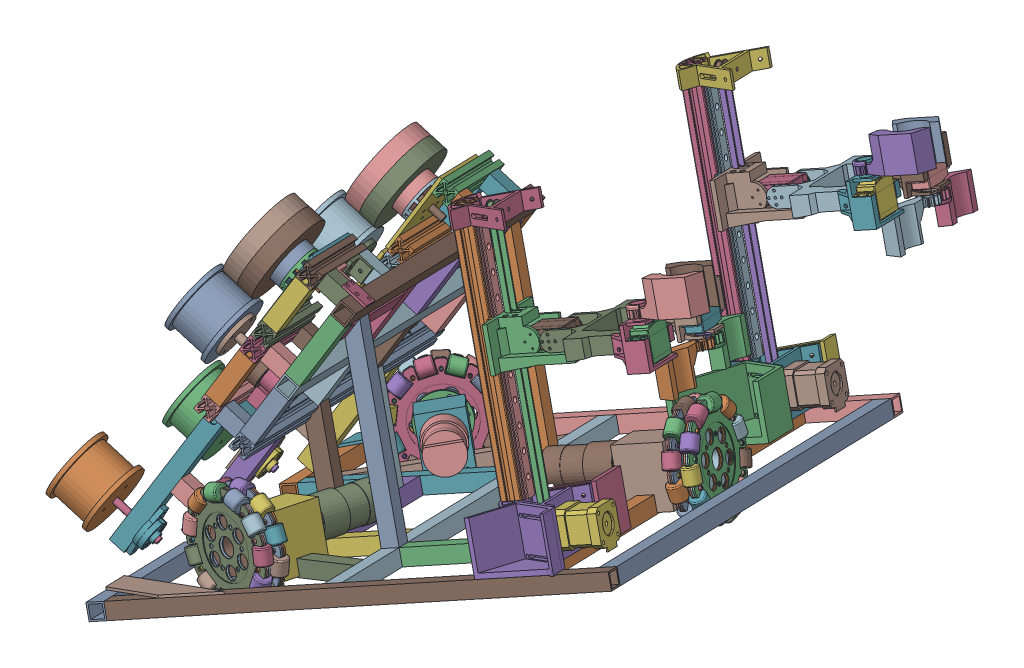
SolidWorks assembly R1 Matlab Sim, configuration Default. Lengths in mm.
Overall size (955.95 722.96 972.76).
16 component instances, 6 part files, 35 mates.
Components (placement in the parent):
- R1 Chassis 6.0^r1 new chassis final part-1: R1 Chassis 6.0^r1 new chassis final part [Default] at (-4184.0722 -937.4255 -3816.6407) x (0.301607 0.282787 0.91053) z (-0.870861 -0.307048 0.383828) size (641.16 369 671.98)
- Omni wheel 127 part-1: Omni wheel 127 part [Default] at (-4602.7717 -1004.8804 -2863.0443) x (0.986722 -0.097143 0.130163) z (-0.118658 0.116072 0.986128) size (127.02 126 38)
- Omni wheel 127 part-2: Omni wheel 127 part [Default] at (-4339.3403 -953.648 -3225.4474) x (0.274362 -0.951568 -0.138723) z (-0.870861 -0.307048 0.383828) size (127.02 126 38)
- Omni wheel 127 part-3: Omni wheel 127 part [Default] at (-4745.1531 -1138.3774 -3292.8838) x (0.680114 -0.674599 -0.286985) z (-0.658494 -0.39008 -0.643601) size (127.02 126 38)
- Flipping_with_dual_shaft part-1: Flipping_with_dual_shaft part [Default] at (-4513.2105 -869.8457 -3469.0567) x (-0.301607 -0.282787 -0.91053) z (0.870861 0.307048 -0.383828) size (100 50 97.1)
- Flipping_with_dual_shaft part-2: Flipping_with_dual_shaft part [Default] at (-4360.7057 -732.4356 -3013.1182) x (-0.301607 -0.282787 -0.91053) z (0.870861 0.307048 -0.383828) size (100 50 97.1)
- Flipping_with_dual_shaft gripper part-1: Flipping_with_dual_shaft gripper part [Default] at (-4514.6412 -878.2751 -3444.5959) x (-0.313424 -0.286937 -0.905225) z (0.907949 0.188715 -0.374185) size (170.89 81.02 142.51)
- Flipping_with_dual_shaft gripper part-2: Flipping_with_dual_shaft gripper part [Default] at (-4362.8301 -741.5154 -2990.7516) x (-0.313424 -0.286937 -0.905225) z (0.907949 0.188715 -0.374185) size (170.89 81.02 142.51)
- gripper v4 gear-1: gripper v4 gear [Metric - Spur gear 1.5M 14T 20PA 10FW ---S14N75H50L3N] at (-4212.9658 -623.4447 -3023.6832) x (-0.388118 0.90871 -0.15366) z (-0.301607 -0.282787 -0.91053) size (40 86 32)
- spur_gear-1: spur_gear [Default] at (-4221.1679 -625.0695 -3042.6017) x (0.388118 -0.90871 0.15366) z (0.48783 0.344021 0.802291) size (40 83.91 29.51)
- spur_gear-2: spur_gear [Default] at (-4375.8917 -844.939 -3571.7047) x (-0.388118 0.90871 -0.15366) z (0.91614 0.362275 -0.171592) size (40 83.91 29.51)
- spur_gear-3: spur_gear [Default] at (-4372.979 -761.8292 -3496.446) x (0.388118 -0.90871 0.15366) z (0.48783 0.344021 0.802291) size (40 83.91 29.51)
- spur_gear-4: spur_gear [Default] at (-4224.0806 -708.1793 -3117.8604) x (-0.388118 0.90871 -0.15366) z (0.91614 0.362275 -0.171592) size (40 83.91 29.51)
- gripper v4 gear-2: gripper v4 gear [Metric - Spur gear 1.5M 14T 20PA 10FW ---S14N75H50L3N] at (-4232.3654 -709.8457 -3136.8161) x (0.388118 -0.90871 0.15366) z (0.870861 0.307048 -0.383828) size (40 86 32)
- gripper v4 gear-3: gripper v4 gear [Metric - Spur gear 1.5M 14T 20PA 10FW ---S14N75H50L3N] at (-4384.1765 -846.6054 -3590.6604) x (0.388118 -0.90871 0.15366) z (0.870861 0.307048 -0.383828) size (40 86 32)
- gripper v4 gear-4: gripper v4 gear [Metric - Spur gear 1.5M 14T 20PA 10FW ---S14N75H50L3N] at (-4364.7769 -760.2044 -3477.5275) x (-0.388118 0.90871 -0.15366) z (-0.301607 -0.282787 -0.91053) size (40 86 32)
Mates (geometry in assembly coordinates):
- Coincident1: coincident anti-aligned: plane of R1 Chassis 6.0^r1 new chassis final part-1 through (-4600.1612 -1007.434 -2884.7391) normal (-0.118658 0.116072 0.986128); plane of Omni wheel 127 part-1 through (-4600.1612 -1007.434 -2884.7391) normal (0.118658 -0.116072 -0.986128)
- Concentric1: concentric anti-aligned: cylinder of R1 Chassis 6.0^r1 new chassis final part-1 through (-4599.6866 -1007.8983 -2888.6836) axis (-0.118658 0.116072 0.986128) radius 29.5; circle of Omni wheel 127 part-1
- Coincident2: coincident anti-aligned: plane of R1 Chassis 6.0^r1 new chassis final part-1 through (-4730.6663 -1129.7956 -3278.7246) normal (-0.658494 -0.39008 -0.643601); plane of Omni wheel 127 part-3 through (-4730.6663 -1129.7956 -3278.7246) normal (0.658494 0.39008 0.643601)
- Concentric2: concentric aligned: circle of R1 Chassis 6.0^r1 new chassis final part-1; circle of Omni wheel 127 part-3
- Coincident3: coincident anti-aligned: plane of R1 Chassis 6.0^r1 new chassis final part-1 through (-4340.2112 -953.9551 -3225.0636) normal (0.870861 0.307048 -0.383828); plane of Omni wheel 127 part-2 through (-4340.2112 -953.9551 -3225.0636) normal (-0.870861 -0.307048 0.383828)
- Concentric3: concentric aligned: cylinder of R1 Chassis 6.0^r1 new chassis final part-1 through (-4343.6946 -955.1833 -3223.5283) axis (0.870861 0.307048 -0.383828) radius 29.5; cylinder of Omni wheel 127 part-2 through (-4328.89 -949.9634 -3230.0534) axis (0.870861 0.307048 -0.383828) radius 11
- Coincident4: coincident anti-aligned: plane of R1 Chassis 6.0^r1 new chassis final part-1 through (-4576.7628 -763.967 -3488.9325) normal (0.870861 0.307048 -0.383828); plane of Flipping_with_dual_shaft part-1 through (-4521.2487 -878.3577 -3454.4858) normal (-0.870861 -0.307048 0.383828)
- Coincident5: coincident anti-aligned: plane of R1 Chassis 6.0^r1 new chassis final part-1 through (-4575.5016 -760.7415 -3473.0434) normal (0.301607 0.282787 0.91053); plane of Flipping_with_dual_shaft part-1 through (-4521.2487 -878.3577 -3454.4858) normal (-0.301607 -0.282787 -0.91053)
- Coincident6: coincident anti-aligned: plane of R1 Chassis 6.0^r1 new chassis final part-1 through (-4425.9593 -622.5735 -3033.6676) normal (0.870861 0.307048 -0.383828); plane of Flipping_with_dual_shaft part-2 through (-4368.7439 -740.9476 -2998.5473) normal (-0.870861 -0.307048 0.383828)
- Coincident7: coincident anti-aligned: plane of R1 Chassis 6.0^r1 new chassis final part-1 through (-4424.6981 -619.348 -3017.7785) normal (0.301607 0.282787 0.91053); plane of Flipping_with_dual_shaft part-2 through (-4368.7439 -740.9476 -2998.5473) normal (-0.301607 -0.282787 -0.91053)
- Concentric4: concentric anti-aligned: cylinder of Flipping_with_dual_shaft part-1 through (-4485.5647 -848.3334 -3509.4406) axis (-0.301607 -0.282787 -0.91053) radius 10; cylinder of Flipping_with_dual_shaft gripper part-1 through (-4499.499 -861.3982 -3551.5071) axis (0.301607 0.282787 0.91053) radius 1.5
- Coincident9: coincident anti-aligned: plane of Flipping_with_dual_shaft part-1 through (-4486.1679 -848.899 -3511.2617) normal (-0.301607 -0.282787 -0.91053); plane of Flipping_with_dual_shaft gripper part-1 through (-4490.6072 -861.9653 -3505.7332) normal (0.301607 0.282787 0.91053)
- Concentric6: concentric aligned: cylinder of Flipping_with_dual_shaft part-2 through (-4319.3971 -698.113 -3012.2551) axis (0.301607 0.282787 0.91053) radius 10; cylinder of Flipping_with_dual_shaft gripper part-2 through (-4347.6879 -724.6385 -3097.6628) axis (0.301607 0.282787 0.91053) radius 1.5
- Coincident11: coincident anti-aligned: plane of Flipping_with_dual_shaft part-2 through (-4318.7939 -697.5475 -3010.434) normal (0.301607 0.282787 0.91053); plane of Flipping_with_dual_shaft gripper part-2 through (-4323.2332 -710.6138 -3004.9055) normal (-0.301607 -0.282787 -0.91053)
- Concentric7: concentric aligned: cylinder of Flipping_with_dual_shaft gripper part-2 through (-4216.9246 -614.1759 -3025.2505) axis (0.388118 -0.90871 0.15366) radius 2.95; cylinder of gripper v4 gear-1 through (-4228.4905 -587.0964 -3029.8296) axis (0.388118 -0.90871 0.15366) radius 3.15
- Distance1: distance = 0.2 mm anti-aligned: plane of gripper v4 gear-1 through (-4216.847 -614.3576 -3025.2198) normal (-0.388118 0.90871 -0.15366); plane of Flipping_with_dual_shaft gripper part-2 through (-4216.9246 -614.1759 -3025.2505) normal (0.388118 -0.90871 0.15366)
- Concentric8: concentric aligned: cylinder of Flipping_with_dual_shaft gripper part-2 through (-4217.6295 -632.9078 -3041.8346) axis (-0.388118 0.90871 -0.15366) radius 10; cylinder of spur_gear-1 through (-4203.2691 -666.5301 -3036.1491) axis (-0.388118 0.90871 -0.15366) radius 1
- Concentric10: concentric aligned: cylinder of Flipping_with_dual_shaft gripper part-2 through (-4228.6721 -698.1108 -3119.0489) axis (0.388118 -0.90871 0.15366) radius 1.5; cylinder of spur_gear-4 through (-4242.0621 -666.7603 -3124.3502) axis (0.388118 -0.90871 0.15366) radius 1
- Concentric11: concentric aligned: cylinder of Flipping_with_dual_shaft gripper part-2 through (-4228.4066 -719.1145 -3135.2488) axis (-0.388118 0.90871 -0.15366) radius 2.95; circle of gripper v4 gear-2
- Distance2: distance = 0.2 mm anti-aligned: plane of gripper v4 gear-2 through (-4228.4842 -718.9328 -3135.2795) normal (0.388118 -0.90871 0.15366); plane of Flipping_with_dual_shaft gripper part-2 through (-4228.4066 -719.1145 -3135.2488) normal (-0.388118 0.90871 -0.15366)
- Concentric13: concentric aligned: cylinder of Flipping_with_dual_shaft gripper part-1 through (-4369.4406 -769.6675 -3495.6789) axis (-0.388118 0.90871 -0.15366) radius 10; cylinder of spur_gear-3 through (-4355.0802 -803.2898 -3489.9935) axis (-0.388118 0.90871 -0.15366) radius 1
- Concentric15: concentric aligned: cylinder of Flipping_with_dual_shaft gripper part-1 through (-4368.7357 -750.9356 -3479.0949) axis (0.388118 -0.90871 0.15366) radius 2.95; cylinder of gripper v4 gear-4 through (-4380.3016 -723.856 -3483.6739) axis (0.388118 -0.90871 0.15366) radius 3.15
- Distance3: distance = 0.2 mm anti-aligned: plane of gripper v4 gear-4 through (-4368.6581 -751.1173 -3479.0641) normal (-0.388118 0.90871 -0.15366); plane of Flipping_with_dual_shaft gripper part-1 through (-4368.7357 -750.9356 -3479.0949) normal (0.388118 -0.90871 0.15366)
- Concentric16: concentric aligned: cylinder of Flipping_with_dual_shaft gripper part-1 through (-4380.2177 -855.8742 -3589.0931) axis (-0.388118 0.90871 -0.15366) radius 2.95; cylinder of gripper v4 gear-3 through (-4368.6518 -882.9537 -3584.514) axis (-0.388118 0.90871 -0.15366) radius 3.15
- Distance4: distance = 0.2 mm anti-aligned: plane of gripper v4 gear-3 through (-4380.2953 -855.6925 -3589.1238) normal (0.388118 -0.90871 0.15366); plane of Flipping_with_dual_shaft gripper part-1 through (-4380.2177 -855.8742 -3589.0931) normal (-0.388118 0.90871 -0.15366)
- Concentric17: concentric anti-aligned: cylinder of Flipping_with_dual_shaft gripper part-1 through (-4379.5129 -837.1423 -3572.5091) axis (0.388118 -0.90871 0.15366) radius 10; circle of spur_gear-2
- Distance10: distance = 2 mm anti-aligned: plane of Flipping_with_dual_shaft gripper part-1 through (-4378.7366 -838.9597 -3572.2017) normal (0.388118 -0.90871 0.15366); plane of spur_gear-2 through (-4377.9604 -840.7771 -3571.8944) normal (-0.388118 0.90871 -0.15366)
- Distance11: distance = 2 mm anti-aligned: plane of spur_gear-3 through (-4370.993 -766.0327 -3496.2936) normal (0.388118 -0.90871 0.15366); plane of Flipping_with_dual_shaft gripper part-1 through (-4370.2168 -767.8501 -3495.9862) normal (-0.388118 0.90871 -0.15366)
- Distance12: distance = 2 mm anti-aligned: plane of Flipping_with_dual_shaft gripper part-2 through (-4218.4057 -631.0904 -3042.1419) normal (-0.388118 0.90871 -0.15366); plane of spur_gear-1 through (-4219.1819 -629.273 -3042.4492) normal (0.388118 -0.90871 0.15366)
- Distance13: distance = 2 mm anti-aligned: plane of spur_gear-4 through (-4226.1493 -704.0174 -3118.0501) normal (-0.388118 0.90871 -0.15366); plane of Flipping_with_dual_shaft gripper part-2 through (-4226.9255 -702.2 -3118.3574) normal (0.388118 -0.90871 0.15366)
- Distance15: distance = 160 mm anti-aligned: plane of Flipping_with_dual_shaft gripper part-1 through (-4421.6537 -820.7501 -3436.1605) normal (0.388118 -0.90871 0.15366); plane of R1 Chassis 6.0^r1 new chassis final part-1 through (-4436.6503 -1003.0084 -3434.8556) normal (-0.388118 0.90871 -0.15366)
- Parallel3: parallel aligned: plane of gripper v4 gear-1 through (-4178.6783 -683.9441 -2994.286) normal (0.301607 0.282787 0.91053); plane of Flipping_with_dual_shaft gripper part-2 through (-4162.9435 -622.489 -3020.078) normal (0.301607 0.282787 0.91053)
- Parallel4: parallel anti-aligned: plane of gripper v4 gear-1 through (-4178.6783 -683.9441 -2994.286) normal (0.301607 0.282787 0.91053); plane of spur_gear-1 through (-4173.3602 -606.1906 -3086.7614) normal (-0.301607 -0.282787 -0.91053)
- Parallel6: parallel aligned: plane of Flipping_with_dual_shaft gripper part-1 through (-4314.7546 -759.2487 -3473.9223) normal (0.301607 0.282787 0.91053); plane of gripper v4 gear-4 through (-4330.4894 -820.7038 -3448.1303) normal (0.301607 0.282787 0.91053)
- Parallel7: parallel anti-aligned: plane of spur_gear-3 through (-4325.1713 -742.9503 -3540.6057) normal (-0.301607 -0.282787 -0.91053); plane of gripper v4 gear-4 through (-4330.4894 -820.7038 -3448.1303) normal (0.301607 0.282787 0.91053)
